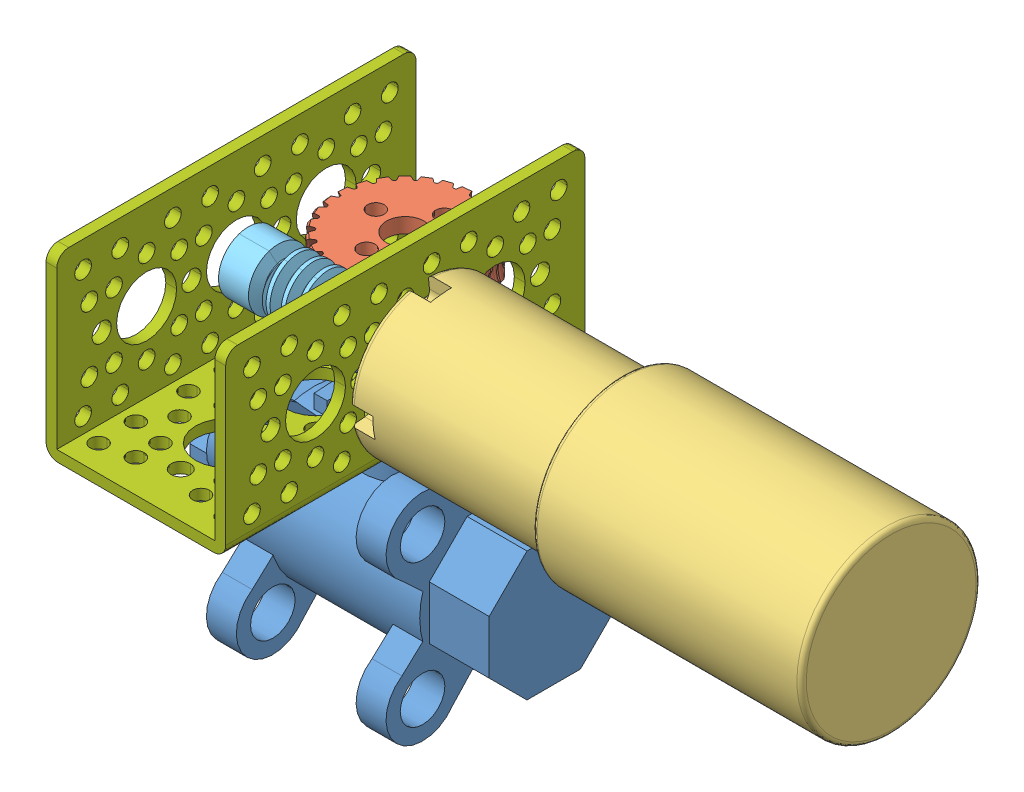
SolidWorks assembly Worm-assembly-test, configuration Default. Lengths in mm.
Overall size (153.83 94.06 80.17).
11 component instances, 8 part files, 13 mates.
Components (placement in the parent):
- Sharpe 39036-1: Sharpe 39036 [Default] at (-31.6615 -12.8372 9.1586) size (63.5 64.02 45.72)
- 615464-1: 615464 [Default] at (-12.6115 36.7952 8.8746) x (0.796374 0 -0.604804) z (0 1 0) size (32.88 32.88 10.4)
- Motor_12VDC_638263-1: Motor_12VDC_638263 [Default] at (7.5731 37.6096 27.9246) x (0 0.995285 0.096992) z (0 -0.096992 0.995285) size (38 101.9 38)
- Motor_12VDC_638263_shaft-1: Motor_12VDC_638263_shaft [Default] at (-8.6269 37.6096 27.9246) x (0 -1 0) z (0 0 1) size (6 16.2 6)
- 615462 assembly-1: 615462 assembly [Default] at (-15.5157 50.6084 27.1723) x (0 0.951654 0.307172) z (1 0 0) size (12.7 13.35 29.62)
  - 615462 assembly.STEP-1: 615462 assembly.STEP [Default] at origin size (12.7 13.35 29.62)
    - 615462.STEP-1: 615462.STEP [Default] at (-12.1392 4.7088 3.3043) size (12.7 13.35 29.25)
    - 632134_91375A436.STEP-1: 632134_91375A436.STEP [Default] at (-12.1392 0.1384 14.7533) x (0.578664 0 0.815566) z (0 -1 0) size (4.83 4.83 3.18)
    - 632134_91375A436.STEP-2: 632134_91375A436.STEP [Default] at (-12.1392 0.1384 -8.1448) x (-0.562691 0 -0.826667) z (0 -1 0) size (4.83 4.83 3.18)
- 585442-1: 585442 [Default] at (-31.6615 18.5596 -10.1754) size (38.1 38.1 76.2)
- Base-sheetmetal-1: Base-sheetmetal [Default] at (-12.5202 17.2896 9.1586) x (1 0 0) z (0 0 -1) size (40.82 46.26 49.53) (hidden)
Mates (geometry in assembly coordinates):
- Concentric1: concentric: circle of Sharpe 39036-1; cylinder of 615464-1 through (-12.6115 15.0247 8.8746) axis (0 1 0) radius 4
- Coincident4: coincident: circle of Motor_12VDC_638263-1; circle of Motor_12VDC_638263_shaft-1
- Concentric2: concentric: circle of Motor_12VDC_638263_shaft-1; circle of 615462 assembly-1/615462 assembly.STEP-1/615462.STEP-1
- Distance1: distance = 5.1605 mm: plane of Motor_12VDC_638263-1 through (7.5731 37.6096 27.9246) normal (-1 0 0); plane of 615462 assembly-1/615462 assembly.STEP-1/615462.STEP-1 through (2.4126 37.6096 27.9246) normal (1 0 0)
- Concentric3: concentric: circle of Sharpe 39036-1; cylinder of 585442-1 through (-12.6115 18.5596 8.8746) axis (0 -1 0) radius 6.3627
- Concentric4: concentric: circle of 615462 assembly-1/615462 assembly.STEP-1/615462.STEP-1; circle of 585442-1
- Concentric5: concentric: cylinder of Sharpe 39036-1 through (-25.3115 2.2758 -5.9544) axis (-1 0 0) radius 4.7307; circle of Base-sheetmetal-1
- Concentric6: concentric: cylinder of Sharpe 39036-1 through (6.4385 2.2758 24.2716) axis (-1 0 0) radius 4.7307; circle of Base-sheetmetal-1
- Coincident7: coincident: plane of Sharpe 39036-1 through (-31.6615 -12.8372 9.1586) normal (-1 0 0); plane of Base-sheetmetal-1 through (-31.6615 36.8833 9.1586) normal (1 0 0)
- Concentric7: concentric: circle of Sharpe 39036-1; cylinder of 585442-1 through (-12.6115 18.5596 8.8746) axis (0 -1 0) radius 6.3627
- Coincident8: coincident: plane of 585442-1 through (6.4385 18.5596 66.0246) normal (0 -1 0); plane of Base-sheetmetal-1 through (-12.5202 18.5596 9.1586) normal (0 1 0)
- Parallel1: parallel: plane of Sharpe 39036-1 through (-44.3615 -12.8372 9.1586) normal (-1 0 0); plane of 585442-1 through (-31.6615 18.5596 66.0246) normal (-1 0 0)
- Distance2: distance = 2.54 mm: plane of 585442-1 through (-29.3755 56.6596 66.0246) normal (1 0 0); plane of 615462 assembly-1/615462 assembly.STEP-1/615462.STEP-1 through (-26.8355 37.6096 27.9246) normal (-1 0 0)
